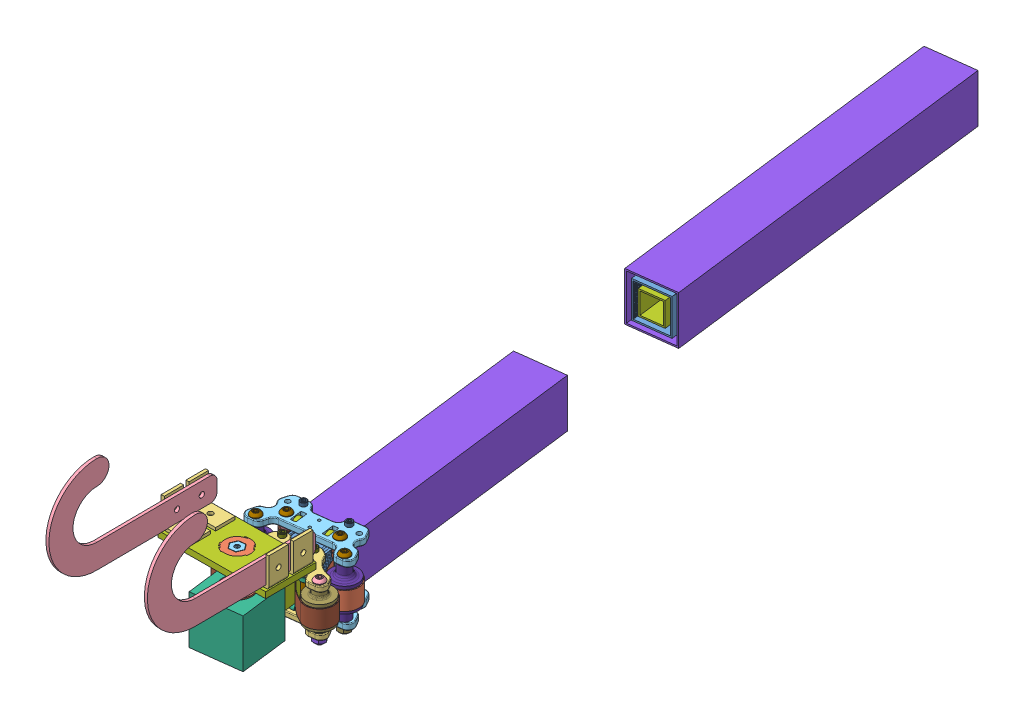
SolidWorks assembly climber prototype3, configuration Default. Lengths in mm.
Overall size (219.65 206.08 1008.89).
107 component instances, 43 part files, 29 mates.
Components (placement in the parent):
- ThriftyTelescopingTube(2)-1: ThriftyTelescopingTube(2) [Default] at origin size (219.65 74.15 857.68)
  - 2 x 2 Inch Stage-1: 2 x 2 Inch Stage [Default] at (1113.4745 353.0023 985.2524) size (183.93 74.15 806.3)
    - 1.5_inch_stage^2 x 2 Inch Stage-1: 1.5_inch_stage^2 x 2 Inch Stage [Default] at (-107.3783 0 -858.4701) size (133.34 47.37 731.79) (virtual)
      - 1.5x1.5 bar^1.5_inch_stage_2 x 2 Inch Stage-1: 1.5x1.5 bar^1.5_inch_stage_2 x 2 Inch Stage [Default] at (575.8182 404.7167 1377.5179) x (-0.992268 0 0.124114) z (-0.124114 0 -0.992268) size (38.1 38.1 711.2) (virtual)
      - 2x2StageInternalEndBlock^1.5_inch_stage_2 x 2 Inch Stage-1: 2x2StageInternalEndBlock^1.5_inch_stage_2 x 2 Inch Stage [Default] at (413.7616 573.8056 681.0462) x (-0.992268 0 0.124114) z (-0.124114 0 -0.992268) size (47.37 47.37 40.64) (virtual)
      - 94615A115_Brass Flanged Screw-to-Expand Inserts (1)^1.5_inch_stage_2 x 2 Inch Stage-1: 94615A115_Brass Flanged Screw-to-Expand Inserts (1)^1.5_inch_stage_2 x 2 Inch Stage [Default] at (431.7042 573.8056 688.4011) x (0.114575 0.384452 0.916007) z (-0.047716 0.923145 -0.381479) size (7.92 9.53 7.92) (virtual)
      - 97763A231_18-8 Stainless Steel Button Head Hex Drive Screws^1.5_inch_stage_2 x 2 Inch Stage-1: 97763A231_18-8 Stainless Steel Button Head Hex Drive Screws^1.5_inch_stage_2 x 2 Inch Stage [Default] at (398.9269 573.8691 692.501) x (0.124114 0.000773 0.992268) z (-0.992268 0 0.124114) size (9.17 9.17 12.09) (virtual)
    - 2x2ClimberPlateAssemblyNew^2 x 2 Inch Stage-1: 2x2ClimberPlateAssemblyNew^2 x 2 Inch Stage [Default] at (310.1471 56.4224 225.65) x (0.992268 0 -0.124114) z (0.124114 0 0.992268) size (102.18 13.04 44.45) (virtual)
      - 2x2NewClimberPlateConcept^2x2ClimberPlateAssemblyNew_2 x 2 Inch Stage-1: 2x2NewClimberPlateConcept^2x2ClimberPlateAssemblyNew_2 x 2 Inch Stage [Default] at (71.6924 542.7705 -285.0056) x (-1 0 0) z (0 1 0) size (102.18 44.45 8.76) (virtual)
      - 98381A545_ALLOY STEEL DOWEL PIN^2x2ClimberPlateAssemblyNew_2 x 2 Inch Stage-1: 98381A545_ALLOY STEEL DOWEL PIN^2x2ClimberPlateAssemblyNew_2 x 2 Inch Stage [Default] at (46.4194 542.6435 281.8589) x (-1 0 0) z (0 -0.467381 0.884056) size (34.92 6.35 6.35) (virtual)
      - TTB-0027_.50OD_.25ID_.188WD^2x2ClimberPlateAssemblyNew_2 x 2 Inch Stage-1: TTB-0027_.50OD_.25ID_.188WD^2x2ClimberPlateAssemblyNew_2 x 2 Inch Stage [Default] at (31.3382 542.6435 281.8589) x (0 0.013886 0.999904) z (-1 0 0) size (12.7 12.7 4.76) (virtual)
      - TTB-0027_.50OD_.25ID_.188WD^2x2ClimberPlateAssemblyNew_2 x 2 Inch Stage-2: TTB-0027_.50OD_.25ID_.188WD^2x2ClimberPlateAssemblyNew_2 x 2 Inch Stage [Default] at (61.5007 542.6435 281.8589) x (0 0.005291 0.999986) z (-1 0 0) size (12.7 12.7 4.76) (virtual)
    - 2x2ClimberPlateAssemblyNew^2 x 2 Inch Stage-2: 2x2ClimberPlateAssemblyNew^2 x 2 Inch Stage [Default] at (402.0161 1091.1635 214.1589) x (-0.992268 0 0.124114) z (0.124114 0 0.992268) size (102.18 13.04 44.45) (virtual)
      - 2x2NewClimberPlateConcept^2x2ClimberPlateAssemblyNew_2 x 2 Inch Stage-1: 2x2NewClimberPlateConcept^2x2ClimberPlateAssemblyNew_2 x 2 Inch Stage [Default] at (71.6924 542.7705 -285.0056) x (-1 0 0) z (0 1 0) size (102.18 44.45 8.76) (virtual)
      - 98381A545_ALLOY STEEL DOWEL PIN^2x2ClimberPlateAssemblyNew_2 x 2 Inch Stage-1: 98381A545_ALLOY STEEL DOWEL PIN^2x2ClimberPlateAssemblyNew_2 x 2 Inch Stage [Default] at (46.4194 542.6435 281.8589) x (-1 0 0) z (0 -0.467381 0.884056) size (34.92 6.35 6.35) (virtual)
      - TTB-0027_.50OD_.25ID_.188WD^2x2ClimberPlateAssemblyNew_2 x 2 Inch Stage-1: TTB-0027_.50OD_.25ID_.188WD^2x2ClimberPlateAssemblyNew_2 x 2 Inch Stage [Default] at (31.3382 542.6435 281.8589) x (0 0.013886 0.999904) z (-1 0 0) size (12.7 12.7 4.76) (virtual)
      - TTB-0027_.50OD_.25ID_.188WD^2x2ClimberPlateAssemblyNew_2 x 2 Inch Stage-2: TTB-0027_.50OD_.25ID_.188WD^2x2ClimberPlateAssemblyNew_2 x 2 Inch Stage [Default] at (61.5007 542.6435 281.8589) x (0 0.005291 0.999986) z (-1 0 0) size (12.7 12.7 4.76) (virtual)
    - 2x2 Box^2 x 2 Inch Stage-1: 2x2 Box^2 x 2 Inch Stage [Default] at (320.6921 548.3929 -267.6788) x (-0.992268 0 0.124114) z (0.124114 0 0.992268) size (50.8 50.8 762) (virtual)
    - 91255A529_NO THREADS_Button Head Hex Drive Screw (1)^2 x 2 Inch Stage-1: 91255A529_NO THREADS_Button Head Hex Drive Screw (1)^2 x 2 Inch Stage [Default] at (366.1553 609.0227 504.1716) x (0.396837 0 -0.917889) z (0 1 0) size (11.1 11.1 73.2) (virtual)
    - 90044A515_Black-Oxide Alloy Steel Socket Head Screw^2 x 2 Inch Stage-1: 90044A515_Black-Oxide Alloy Steel Socket Head Screw^2 x 2 Inch Stage [Default] at (410.673 605.6699 482.6046) x (0.993633 0 -0.112668) z (0 1 0) size (6.86 6.86 74.15) (virtual)
    - 90044A515_Black-Oxide Alloy Steel Socket Head Screw^2 x 2 Inch Stage-2: 90044A515_Black-Oxide Alloy Steel Socket Head Screw^2 x 2 Inch Stage [Default] at (367.8773 605.6699 487.9575) x (0.430705 0 0.902493) z (0 1 0) size (6.86 6.86 74.15) (virtual)
    - 91255A529_NO THREADS_Button Head Hex Drive Screw (1)^2 x 2 Inch Stage-2: 91255A529_NO THREADS_Button Head Hex Drive Screw (1)^2 x 2 Inch Stage [Default] at (351.7432 609.0227 521.973) x (-0.099638 0 0.995024) z (0 1 0) size (11.1 11.1 73.2) (virtual)
    - 91255A529_NO THREADS_Button Head Hex Drive Screw (1)^2 x 2 Inch Stage-3: 91255A529_NO THREADS_Button Head Hex Drive Screw (1)^2 x 2 Inch Stage [Default] at (434.6883 609.0227 511.5981) x (1 0 0) z (0 1 0) size (11.1 11.1 73.2) (virtual)
    - 91255A529_NO THREADS_Button Head Hex Drive Screw (1)^2 x 2 Inch Stage-4: 91255A529_NO THREADS_Button Head Hex Drive Screw (1)^2 x 2 Inch Stage [Default] at (416.3356 609.0227 497.895) x (0.998718 0 -0.050617) z (0 1 0) size (11.1 11.1 73.2) (virtual)
    - TTB-0027_.50OD_.25ID_.188WD^2 x 2 Inch Stage-1: TTB-0027_.50OD_.25ID_.188WD^2 x 2 Inch Stage [Default] at (416.3356 557.2004 497.895) x (-0.032207 0 0.999481) z (0 1 0) size (12.7 12.7 4.76) (virtual)
    - TTB-0027_.50OD_.25ID_.188WD^2 x 2 Inch Stage-2: TTB-0027_.50OD_.25ID_.188WD^2 x 2 Inch Stage [Default] at (416.3356 590.4617 497.895) x (-0.065423 0 0.997858) z (0 1 0) size (12.7 12.7 4.76) (virtual)
    - TTB-0027_.50OD_.25ID_.188WD^2 x 2 Inch Stage-3: TTB-0027_.50OD_.25ID_.188WD^2 x 2 Inch Stage [Default] at (366.1553 557.2004 504.1716) x (-0.065423 0 0.997858) z (0 1 0) size (12.7 12.7 4.76) (virtual)
    - TTB-0027_.50OD_.25ID_.188WD^2 x 2 Inch Stage-4: TTB-0027_.50OD_.25ID_.188WD^2 x 2 Inch Stage [Default] at (366.1553 590.4617 504.1716) x (-0.065423 0 0.997858) z (0 1 0) size (12.7 12.7 4.76) (virtual)
    - 90101A230_18-8 Stainless Steel Thin Nylon-Insert Locknut^2 x 2 Inch Stage-1: 90101A230_18-8 Stainless Steel Thin Nylon-Insert Locknut^2 x 2 Inch Stage [Default] at (434.6883 541.9159 511.5981) x (0.797272 0 -0.60362) z (-0.60362 0 -0.797272) size (11.11 5.2 12.83) (virtual)
    - 90101A230_18-8 Stainless Steel Thin Nylon-Insert Locknut^2 x 2 Inch Stage-2: 90101A230_18-8 Stainless Steel Thin Nylon-Insert Locknut^2 x 2 Inch Stage [Default] at (416.3356 541.9159 497.895) x (0.921386 0 0.388648) z (0.388648 0 -0.921386) size (11.11 5.2 12.83) (virtual)
    - 90101A230_18-8 Stainless Steel Thin Nylon-Insert Locknut^2 x 2 Inch Stage-3: 90101A230_18-8 Stainless Steel Thin Nylon-Insert Locknut^2 x 2 Inch Stage [Default] at (351.7432 541.9159 521.973) x (0.797272 0 -0.60362) z (-0.60362 0 -0.797272) size (11.11 5.2 12.83) (virtual)
    - 90101A230_18-8 Stainless Steel Thin Nylon-Insert Locknut^2 x 2 Inch Stage-4: 90101A230_18-8 Stainless Steel Thin Nylon-Insert Locknut^2 x 2 Inch Stage [Default] at (366.1553 541.9159 504.1716) x (0.797272 0 -0.60362) z (-0.60362 0 -0.797272) size (11.11 5.2 12.83) (virtual)
    - QuaterInchTelescopingSpacer^2 x 2 Inch Stage-1: QuaterInchTelescopingSpacer^2 x 2 Inch Stage [Default] at (391.2422 599.1929 504.1716) x (1 0 0) z (0 -1 0) size (9.27 9.27 6.35) (virtual)
    - QuaterInchTelescopingSpacer^2 x 2 Inch Stage-2: QuaterInchTelescopingSpacer^2 x 2 Inch Stage [Default] at (391.2422 554.8191 504.1844) x (1 0 0.000511) z (0 -1 0) size (9.27 9.27 6.35) (virtual)
    - 1.122InchTelescopingSpacer^2 x 2 Inch Stage-1: 1.122InchTelescopingSpacer^2 x 2 Inch Stage [Default] at (391.2422 588.0804 504.1716) x (1 0 0) z (0 -1 0) size (8.76 8.76 28.5) (virtual)
    - QuaterInchTelescopingSpacer^2 x 2 Inch Stage-3: QuaterInchTelescopingSpacer^2 x 2 Inch Stage [Default] at (440.4399 599.1929 504.8475) x (0.96083 0 0.277139) z (0 -1 0) size (9.27 9.27 6.35) (virtual)
    - QuaterInchTelescopingSpacer^2 x 2 Inch Stage-4: QuaterInchTelescopingSpacer^2 x 2 Inch Stage [Default] at (409.5553 554.8191 522.0482) x (-0.270275 0 0.962783) z (0 -1 0) size (9.27 9.27 6.35) (virtual)
    - 94615A115_Brass Flanged Screw-to-Expand Inserts (1)^2 x 2 Inch Stage-1: 94615A115_Brass Flanged Screw-to-Expand Inserts (1)^2 x 2 Inch Stage [Default] at (290.8052 573.8056 -165.8762) x (0.123955 0.050546 0.991) z (0.006274 -0.998722 0.050156) size (7.92 9.53 7.92) (virtual)
    - 97763A231_18-8 Stainless Steel Button Head Hex Drive Screws^2 x 2 Inch Stage-1: 97763A231_18-8 Stainless Steel Button Head Hex Drive Screws^2 x 2 Inch Stage [Default] at (323.7085 573.8691 -169.9917) x (-0.124114 0 -0.992268) z (0.992268 0 -0.124114) size (9.17 9.17 12.09) (virtual)
    - 1.122InchTelescopingSpacer^2 x 2 Inch Stage-2: 1.122InchTelescopingSpacer^2 x 2 Inch Stage [Default] at (441.4226 588.0804 497.895) x (1 0 0) z (0 -1 0) size (8.76 8.76 28.5) (virtual)
    - 1InchCFSpringRetentionSpacer_BaseStage^2 x 2 Inch Stage-1: 1InchCFSpringRetentionSpacer_BaseStage^2 x 2 Inch Stage [Default] at (351.7432 564.2679 521.973) x (1 0 0) z (0 -1 0) size (27.94 27.94 15.88) (virtual)
    - 1InchCFSpringRetentionSpacer_BaseStage^2 x 2 Inch Stage-2: 1InchCFSpringRetentionSpacer_BaseStage^2 x 2 Inch Stage [Default] at (434.6883 583.3179 511.5981) x (-0.043542 0 0.999052) z (0 1 0) size (27.94 27.94 15.88) (virtual)
    - 1InchCFSpringRetentionSpacer_BaseStage^2 x 2 Inch Stage-3: 1InchCFSpringRetentionSpacer_BaseStage^2 x 2 Inch Stage [Default] at (351.7432 583.3179 521.973) x (1 0 0) z (0 1 0) size (27.94 27.94 15.88) (virtual)
    - 1InchCFSpringRetentionSpacer_BaseStage^2 x 2 Inch Stage-4: 1InchCFSpringRetentionSpacer_BaseStage^2 x 2 Inch Stage [Default] at (434.6883 564.2679 511.5981) x (0.999991 0 -0.00417) z (0 -1 0) size (27.94 27.94 15.88) (virtual)
    - 90101A009_18-8 Stainless Steel Thin Nylon-Insert Locknut (1)^2 x 2 Inch Stage-1: 90101A009_18-8 Stainless Steel Thin Nylon-Insert Locknut (1)^2 x 2 Inch Stage [Default] at (368.252 541.9159 487.9106) x (0.797272 0 -0.60362) z (-0.60362 0 -0.797272) size (8.73 4.37 10.08) (virtual)
    - 9293K56_SpringRoller^2 x 2 Inch Stage-1: 9293K56_SpringRoller^2 x 2 Inch Stage [Default] at (351.7432 564.2679 521.973) x (0.41705 0 -0.908884) z (0 1 0) size (20.07 20.07 19.05) (virtual)
    - 9293K56_SpringRoller^2 x 2 Inch Stage-2: 9293K56_SpringRoller^2 x 2 Inch Stage [Default] at (434.6883 583.3179 511.5981) x (0.41705 0 0.908884) z (0 -1 0) size (20.07 20.07 19.05) (virtual)
    - 9293K56_Constant-Force Spring^2 x 2 Inch Stage-1: 9293K56_Constant-Force Spring^2 x 2 Inch Stage [Default] at (434.7326 573.7929 511.5599) x (0 -1 0) z (-0.934501 0 0.355959) size (19.06 41.04 33.21) (virtual)
    - 9293K56_Constant-Force Spring^2 x 2 Inch Stage-2: 9293K56_Constant-Force Spring^2 x 2 Inch Stage [Default] at (351.6902 573.7929 521.9484) x (0 1 0) z (0.996341 0 0.085466) size (19.06 41.04 33.21) (virtual)
    - 90101A009_18-8 Stainless Steel Thin Nylon-Insert Locknut (1)^2 x 2 Inch Stage-2: 90101A009_18-8 Stainless Steel Thin Nylon-Insert Locknut (1)^2 x 2 Inch Stage [Default] at (410.673 541.9159 482.6046) x (0.797272 0 -0.60362) z (-0.60362 0 -0.797272) size (8.73 4.37 10.08) (virtual)
  - Stage 2 BOM - 1.5 inch to 1 inch Kit^ThriftyTelescopingTube(2)-1: Stage 2 BOM - 1.5 inch to 1 inch Kit^ThriftyTelescopingTube(2) [Default] at (1071.3002 772.575 539.439) x (0.992268 0 -0.124114) z (0.124114 0 0.992268) size (125.22 66.32 768.66) (virtual)
    - 1.5ClimberPlateNewDesign^Stage 2 BOM - 1.5 inch to 1 inch Kit_ThriftyTelescopingTube(2)-1: 1.5ClimberPlateNewDesign^Stage 2 BOM - 1.5 inch to 1 inch Kit_ThriftyTelescopingTube(2) [Default] at (293.5653 129.5314 1017.7273) x (1 0 0) z (0 1 0) size (98.65 41.27 8) (virtual)
    - 1.5ClimberPlateNewDesign^Stage 2 BOM - 1.5 inch to 1 inch Kit_ThriftyTelescopingTube(2)-2: 1.5ClimberPlateNewDesign^Stage 2 BOM - 1.5 inch to 1 inch Kit_ThriftyTelescopingTube(2) [Default] at (331.6653 179.0614 1017.7273) x (-1 0 0) z (0 -1 0) size (98.65 41.27 8) (virtual)
    - 91255A528_NO THREADS_Button Head Hex Drive Screw^Stage 2 BOM - 1.5 inch to 1 inch Kit_ThriftyTelescopingTube(2)-1: 91255A528_NO THREADS_Button Head Hex Drive Screw^Stage 2 BOM - 1.5 inch to 1 inch Kit_ThriftyTelescopingTube(2) [Default] at (354.2078 182.4142 1039.3173) x (0.997583 0 0.069478) z (0 1 0) size (11.1 11.1 60.5) (virtual)
    - 91255A528_NO THREADS_Button Head Hex Drive Screw^Stage 2 BOM - 1.5 inch to 1 inch Kit_ThriftyTelescopingTube(2)-2: 91255A528_NO THREADS_Button Head Hex Drive Screw^Stage 2 BOM - 1.5 inch to 1 inch Kit_ThriftyTelescopingTube(2) [Default] at (331.551 182.4142 1025.9823) x (1 0 0.000115) z (0 1 0) size (11.1 11.1 60.5) (virtual)
    - 91255A528_NO THREADS_Button Head Hex Drive Screw^Stage 2 BOM - 1.5 inch to 1 inch Kit_ThriftyTelescopingTube(2)-3: 91255A528_NO THREADS_Button Head Hex Drive Screw^Stage 2 BOM - 1.5 inch to 1 inch Kit_ThriftyTelescopingTube(2) [Default] at (293.6796 182.4142 1025.9823) x (0.942114 0 0.335293) z (0 1 0) size (11.1 11.1 60.5) (virtual)
    - 91255A528_NO THREADS_Button Head Hex Drive Screw^Stage 2 BOM - 1.5 inch to 1 inch Kit_ThriftyTelescopingTube(2)-4: 91255A528_NO THREADS_Button Head Hex Drive Screw^Stage 2 BOM - 1.5 inch to 1 inch Kit_ThriftyTelescopingTube(2) [Default] at (271.0228 182.4142 1039.3173) x (1 0 0) z (0 1 0) size (11.1 11.1 60.5) (virtual)
    - 98381A542_ALLOY STEEL DOWEL PIN^Stage 2 BOM - 1.5 inch to 1 inch Kit_ThriftyTelescopingTube(2)-1: 98381A542_ALLOY STEEL DOWEL PIN^Stage 2 BOM - 1.5 inch to 1 inch Kit_ThriftyTelescopingTube(2) [Default] at (312.5899 173.2194 1025.9545) x (1 0 0) z (0 -0.047568 0.998868) size (25.4 6.35 6.35) (virtual)
    - 98381A542_ALLOY STEEL DOWEL PIN^Stage 2 BOM - 1.5 inch to 1 inch Kit_ThriftyTelescopingTube(2)-2: 98381A542_ALLOY STEEL DOWEL PIN^Stage 2 BOM - 1.5 inch to 1 inch Kit_ThriftyTelescopingTube(2) [Default] at (312.5899 135.3734 1025.9545) x (1 0 0) z (0 -0.129807 0.991539) size (25.4 6.35 6.35) (virtual)
    - TTB-0027_.50OD_.25ID_.188WD^Stage 2 BOM - 1.5 inch to 1 inch Kit_ThriftyTelescopingTube(2)-1: TTB-0027_.50OD_.25ID_.188WD^Stage 2 BOM - 1.5 inch to 1 inch Kit_ThriftyTelescopingTube(2) [Default] at (322.7054 135.3734 1025.9545) x (0 -0.059569 0.998224) z (-1 0 0) size (12.7 12.7 4.76) (virtual)
    - TTB-0027_.50OD_.25ID_.188WD^Stage 2 BOM - 1.5 inch to 1 inch Kit_ThriftyTelescopingTube(2)-2: TTB-0027_.50OD_.25ID_.188WD^Stage 2 BOM - 1.5 inch to 1 inch Kit_ThriftyTelescopingTube(2) [Default] at (302.4743 135.3734 1025.9545) x (0 0.249065 0.968487) z (-1 0 0) size (12.7 12.7 4.76) (virtual)
    - TTB-0027_.50OD_.25ID_.188WD^Stage 2 BOM - 1.5 inch to 1 inch Kit_ThriftyTelescopingTube(2)-3: TTB-0027_.50OD_.25ID_.188WD^Stage 2 BOM - 1.5 inch to 1 inch Kit_ThriftyTelescopingTube(2) [Default] at (293.6796 166.19 1025.9823) x (-0.99026 0 0.139228) z (0 1 0) size (12.7 12.7 4.76) (virtual)
    - TTB-0027_.50OD_.25ID_.188WD^Stage 2 BOM - 1.5 inch to 1 inch Kit_ThriftyTelescopingTube(2)-4: TTB-0027_.50OD_.25ID_.188WD^Stage 2 BOM - 1.5 inch to 1 inch Kit_ThriftyTelescopingTube(2) [Default] at (293.6796 142.2505 1025.9823) x (1 0 0) z (0 1 0) size (12.7 12.7 4.76) (virtual)
    - TTB-0027_.50OD_.25ID_.188WD^Stage 2 BOM - 1.5 inch to 1 inch Kit_ThriftyTelescopingTube(2)-5: TTB-0027_.50OD_.25ID_.188WD^Stage 2 BOM - 1.5 inch to 1 inch Kit_ThriftyTelescopingTube(2) [Default] at (331.551 166.19 1025.9823) x (-0.070413 0 0.997518) z (0 1 0) size (12.7 12.7 4.76) (virtual)
    - TTB-0027_.50OD_.25ID_.188WD^Stage 2 BOM - 1.5 inch to 1 inch Kit_ThriftyTelescopingTube(2)-6: TTB-0027_.50OD_.25ID_.188WD^Stage 2 BOM - 1.5 inch to 1 inch Kit_ThriftyTelescopingTube(2) [Default] at (302.4743 173.2194 1025.9545) x (0 -0.065423 0.997858) z (-1 0 0) size (12.7 12.7 4.76) (virtual)
    - TTB-0027_.50OD_.25ID_.188WD^Stage 2 BOM - 1.5 inch to 1 inch Kit_ThriftyTelescopingTube(2)-7: TTB-0027_.50OD_.25ID_.188WD^Stage 2 BOM - 1.5 inch to 1 inch Kit_ThriftyTelescopingTube(2) [Default] at (322.7054 173.2194 1025.9545) x (0 0.136778 0.990602) z (-1 0 0) size (12.7 12.7 4.76) (virtual)
    - TTB-0027_.50OD_.25ID_.188WD^Stage 2 BOM - 1.5 inch to 1 inch Kit_ThriftyTelescopingTube(2)-8: TTB-0027_.50OD_.25ID_.188WD^Stage 2 BOM - 1.5 inch to 1 inch Kit_ThriftyTelescopingTube(2) [Default] at (331.551 142.2505 1025.9823) x (1 0 0) z (0 1 0) size (12.7 12.7 4.76) (virtual)
    - 1x1^Stage 2 BOM - 1.5 inch to 1 inch Kit_ThriftyTelescopingTube(2)-1: 1x1^Stage 2 BOM - 1.5 inch to 1 inch Kit_ThriftyTelescopingTube(2) [Default] at (299.8518 166.9329 770.3868) x (0 -1 0) z (-1 0 0) size (25.4 711.2 25.4) (virtual)
    - 90101A230_18-8 Stainless Steel Thin Nylon-Insert Locknut^Stage 2 BOM - 1.5 inch to 1 inch Kit_ThriftyTelescopingTube(2)-1: 90101A230_18-8 Stainless Steel Thin Nylon-Insert Locknut^Stage 2 BOM - 1.5 inch to 1 inch Kit_ThriftyTelescopingTube(2) [Default] at (293.6796 129.5314 1025.9823) x (0.866025 0 -0.5) z (-0.5 0 -0.866025) size (11.11 5.2 12.83) (virtual)
    - 90101A230_18-8 Stainless Steel Thin Nylon-Insert Locknut^Stage 2 BOM - 1.5 inch to 1 inch Kit_ThriftyTelescopingTube(2)-2: 90101A230_18-8 Stainless Steel Thin Nylon-Insert Locknut^Stage 2 BOM - 1.5 inch to 1 inch Kit_ThriftyTelescopingTube(2) [Default] at (354.2078 129.5314 1039.3173) x (-0.866025 0 -0.5) z (-0.5 0 0.866025) size (11.11 5.2 12.83) (virtual)
    - 90101A230_18-8 Stainless Steel Thin Nylon-Insert Locknut^Stage 2 BOM - 1.5 inch to 1 inch Kit_ThriftyTelescopingTube(2)-3: 90101A230_18-8 Stainless Steel Thin Nylon-Insert Locknut^Stage 2 BOM - 1.5 inch to 1 inch Kit_ThriftyTelescopingTube(2) [Default] at (331.551 129.5314 1025.9823) x (0.866025 0 0.5) z (0.5 0 -0.866025) size (11.11 5.2 12.83) (virtual)
    - 90101A230_18-8 Stainless Steel Thin Nylon-Insert Locknut^Stage 2 BOM - 1.5 inch to 1 inch Kit_ThriftyTelescopingTube(2)-4: 90101A230_18-8 Stainless Steel Thin Nylon-Insert Locknut^Stage 2 BOM - 1.5 inch to 1 inch Kit_ThriftyTelescopingTube(2) [Default] at (271.0228 129.5314 1039.3173) x (0.866025 0 0.5) z (0.5 0 -0.866025) size (11.11 5.2 12.83) (virtual)
    - .607TelescopingSpacer^Stage 2 BOM - 1.5 inch to 1 inch Kit_ThriftyTelescopingTube(2)-1: .607TelescopingSpacer^Stage 2 BOM - 1.5 inch to 1 inch Kit_ThriftyTelescopingTube(2) [Default] at (354.9872 144.6317 1017.0327) x (0.934202 0 -0.356745) z (0 1 0) size (9.02 9.02 19.18) (virtual)
    - .607TelescopingSpacer^Stage 2 BOM - 1.5 inch to 1 inch Kit_ThriftyTelescopingTube(2)-2: .607TelescopingSpacer^Stage 2 BOM - 1.5 inch to 1 inch Kit_ThriftyTelescopingTube(2) [Default] at (318.7665 144.6317 1026.006) x (1 0 0.000943) z (0 1 0) size (9.02 9.02 19.18) (virtual)
    - .188TelescopingSpacer^Stage 2 BOM - 1.5 inch to 1 inch Kit_ThriftyTelescopingTube(2)-1: .188TelescopingSpacer^Stage 2 BOM - 1.5 inch to 1 inch Kit_ThriftyTelescopingTube(2) [Default] at (356.6379 173.3464 1025.9823) x (1 0 0) z (0 -1 0) size (8.81 8.81 4.78) (virtual)
    - .188TelescopingSpacer^Stage 2 BOM - 1.5 inch to 1 inch Kit_ThriftyTelescopingTube(2)-2: .188TelescopingSpacer^Stage 2 BOM - 1.5 inch to 1 inch Kit_ThriftyTelescopingTube(2) [Default] at (318.7665 173.3464 1025.9823) x (1 0 0) z (0 -1 0) size (8.81 8.81 4.78) (virtual)
    - .188TelescopingSpacer^Stage 2 BOM - 1.5 inch to 1 inch Kit_ThriftyTelescopingTube(2)-3: .188TelescopingSpacer^Stage 2 BOM - 1.5 inch to 1 inch Kit_ThriftyTelescopingTube(2) [Default] at (282.8338 139.8692 1048.6036) x (-0.432328 0 0.901716) z (0 -1 0) size (8.81 8.81 4.78) (virtual)
    - .188TelescopingSpacer^Stage 2 BOM - 1.5 inch to 1 inch Kit_ThriftyTelescopingTube(2)-4: .188TelescopingSpacer^Stage 2 BOM - 1.5 inch to 1 inch Kit_ThriftyTelescopingTube(2) [Default] at (326.9008 139.8692 1001.3302) x (-0.18536 0 -0.982671) z (0 -1 0) size (8.81 8.81 4.78) (virtual)
    - 9293K56_Constant-Force Spring^Stage 2 BOM - 1.5 inch to 1 inch Kit_ThriftyTelescopingTube(2)-1: 9293K56_Constant-Force Spring^Stage 2 BOM - 1.5 inch to 1 inch Kit_ThriftyTelescopingTube(2) [Default] at (354.2389 154.2964 1039.2678) x (0 -1 0) z (-0.788944 0 0.614465) size (19.06 41.04 33.21) (virtual)
    - 1InchCFSpringRetentionSpacer^Stage 2 BOM - 1.5 inch to 1 inch Kit_ThriftyTelescopingTube(2)-1: 1InchCFSpringRetentionSpacer^Stage 2 BOM - 1.5 inch to 1 inch Kit_ThriftyTelescopingTube(2) [Default] at (271.0228 144.7714 1039.3173) x (0.41705 0 0.908884) z (0 -1 0) size (27.94 27.94 9.53) (virtual)
    - 1InchCFSpringRetentionSpacer^Stage 2 BOM - 1.5 inch to 1 inch Kit_ThriftyTelescopingTube(2)-2: 1InchCFSpringRetentionSpacer^Stage 2 BOM - 1.5 inch to 1 inch Kit_ThriftyTelescopingTube(2) [Default] at (354.2078 144.7714 1039.3173) x (0.383782 0 0.923424) z (0 -1 0) size (27.94 27.94 9.53) (virtual)
    - 1InchCFSpringRetentionSpacer^Stage 2 BOM - 1.5 inch to 1 inch Kit_ThriftyTelescopingTube(2)-3: 1InchCFSpringRetentionSpacer^Stage 2 BOM - 1.5 inch to 1 inch Kit_ThriftyTelescopingTube(2) [Default] at (354.2078 163.8214 1039.3173) x (0.830028 0 -0.557722) z (0 1 0) size (27.94 27.94 9.53) (virtual)
    - 1InchCFSpringRetentionSpacer^Stage 2 BOM - 1.5 inch to 1 inch Kit_ThriftyTelescopingTube(2)-4: 1InchCFSpringRetentionSpacer^Stage 2 BOM - 1.5 inch to 1 inch Kit_ThriftyTelescopingTube(2) [Default] at (271.0228 163.8214 1039.3173) x (0.383782 0 -0.923424) z (0 1 0) size (27.94 27.94 9.53) (virtual)
    - 9293K56_Constant-Force Spring^Stage 2 BOM - 1.5 inch to 1 inch Kit_ThriftyTelescopingTube(2)-2: 9293K56_Constant-Force Spring^Stage 2 BOM - 1.5 inch to 1 inch Kit_ThriftyTelescopingTube(2) [Default] at (270.9861 154.2964 1039.2718) x (0 1 0) z (0.855643 0 0.517566) size (19.06 41.04 33.21) (virtual)
    - 9293K56_SpringRoller^Stage 2 BOM - 1.5 inch to 1 inch Kit_ThriftyTelescopingTube(2)-1: 9293K56_SpringRoller^Stage 2 BOM - 1.5 inch to 1 inch Kit_ThriftyTelescopingTube(2) [Default] at (271.0228 163.8214 1039.3173) x (0.416799 0 0.908999) z (0 -1 0) size (20.07 20.07 19.05) (virtual)
    - 1x1StageInternalEndBlock^Stage 2 BOM - 1.5 inch to 1 inch Kit_ThriftyTelescopingTube(2)-1: 1x1StageInternalEndBlock^Stage 2 BOM - 1.5 inch to 1 inch Kit_ThriftyTelescopingTube(2) [Default] at (312.6153 154.2964 363.9868) x (-1 0 0) z (0 0 -1) size (34.67 34.67 40) (virtual)
    - 90101A009_18-8 Stainless Steel Thin Nylon-Insert Locknut (1)^Stage 2 BOM - 1.5 inch to 1 inch Kit_ThriftyTelescopingTube(2)-1: 90101A009_18-8 Stainless Steel Thin Nylon-Insert Locknut (1)^Stage 2 BOM - 1.5 inch to 1 inch Kit_ThriftyTelescopingTube(2) [Default] at (327.8299 129.5314 1011.3773) x (0.866025 0 0.5) z (0.5 0 -0.866025) size (8.73 4.37 10.08) (virtual)
    - 90101A009_18-8 Stainless Steel Thin Nylon-Insert Locknut (1)^Stage 2 BOM - 1.5 inch to 1 inch Kit_ThriftyTelescopingTube(2)-2: 90101A009_18-8 Stainless Steel Thin Nylon-Insert Locknut (1)^Stage 2 BOM - 1.5 inch to 1 inch Kit_ThriftyTelescopingTube(2) [Default] at (297.4007 129.5314 1011.3773) x (-0.866025 0 -0.5) z (-0.5 0 0.866025) size (8.73 4.37 10.08) (virtual)
    - 90044A513_Black-Oxide Alloy Steel Socket Head Screw^Stage 2 BOM - 1.5 inch to 1 inch Kit_ThriftyTelescopingTube(2)-1: 90044A513_Black-Oxide Alloy Steel Socket Head Screw^Stage 2 BOM - 1.5 inch to 1 inch Kit_ThriftyTelescopingTube(2) [Default] at (297.4007 179.0614 1011.3773) x (0.353324 0 0.935501) z (0 1 0) size (10.11 10 66.32) (virtual)
    - 90044A513_Black-Oxide Alloy Steel Socket Head Screw^Stage 2 BOM - 1.5 inch to 1 inch Kit_ThriftyTelescopingTube(2)-2: 90044A513_Black-Oxide Alloy Steel Socket Head Screw^Stage 2 BOM - 1.5 inch to 1 inch Kit_ThriftyTelescopingTube(2) [Default] at (327.8299 179.0614 1011.3773) x (1 0 0) z (0 1 0) size (10.11 10 66.32) (virtual)
    - 94615A212_Brass Flanged Screw-to-Expand Inserts (1)^Stage 2 BOM - 1.5 inch to 1 inch Kit_ThriftyTelescopingTube(2)-1: 94615A212_Brass Flanged Screw-to-Expand Inserts (1)^Stage 2 BOM - 1.5 inch to 1 inch Kit_ThriftyTelescopingTube(2) [Default] at (301.9473 154.2964 373.5118) x (0 -0.59679 -0.802398) z (0 0.802398 -0.59679) size (7.14 7.14 7.14) (virtual)
    - 94615A212_Brass Flanged Screw-to-Expand Inserts (1)^Stage 2 BOM - 1.5 inch to 1 inch Kit_ThriftyTelescopingTube(2)-2: 94615A212_Brass Flanged Screw-to-Expand Inserts (1)^Stage 2 BOM - 1.5 inch to 1 inch Kit_ThriftyTelescopingTube(2) [Default] at (323.2833 154.2964 373.5118) x (0 0.670342 -0.742052) z (0 -0.742052 -0.670342) size (7.14 7.14 7.14) (virtual)
    - 97763A504_18-8 Stainless Steel Button Head Hex Drive Screws^Stage 2 BOM - 1.5 inch to 1 inch Kit_ThriftyTelescopingTube(2)-1: 97763A504_18-8 Stainless Steel Button Head Hex Drive Screws^Stage 2 BOM - 1.5 inch to 1 inch Kit_ThriftyTelescopingTube(2) [Default] at (302.0806 154.2964 373.5118) x (0 0 1) z (-1 0 0) size (7.92 7.92 10.15) (virtual)
    - 97763A504_18-8 Stainless Steel Button Head Hex Drive Screws^Stage 2 BOM - 1.5 inch to 1 inch Kit_ThriftyTelescopingTube(2)-2: 97763A504_18-8 Stainless Steel Button Head Hex Drive Screws^Stage 2 BOM - 1.5 inch to 1 inch Kit_ThriftyTelescopingTube(2) [Default] at (323.0229 154.2964 373.5118) x (0 0 -1) z (1 0 0) size (7.92 7.92 10.15) (virtual)
    - 1.5x1.5 bar^Stage 2 BOM - 1.5 inch to 1 inch Kit_ThriftyTelescopingTube(2)-1: 1.5x1.5 bar^Stage 2 BOM - 1.5 inch to 1 inch Kit_ThriftyTelescopingTube(2) [Default] at (386.9135 -14.856 1017.7273) x (-1 0 0) z (0 0 -1) size (38.1 38.1 711.2) (virtual)
    - 9293K56_SpringRoller^Stage 2 BOM - 1.5 inch to 1 inch Kit_ThriftyTelescopingTube(2)-2: 9293K56_SpringRoller^Stage 2 BOM - 1.5 inch to 1 inch Kit_ThriftyTelescopingTube(2) [Default] at (354.2078 163.8214 1039.3173) x (0.416799 0 0.908999) z (0 -1 0) size (20.07 20.07 19.05) (virtual)
- half in hex bearing for clibmer-1: half in hex bearing for clibmer [Default] at (1516.0789 990.308 1577.6097) x (0.992268 0 -0.124114) z (0 -1 0) size (31.12 31.12 7.93)
- Bracket for climber prototype-3: Bracket for climber prototype [Default] at (1475.5943 991.8955 1601.2458) x (-0.999978 0 0.006611) z (-0.006611 0 -0.999978) size (30.99 30.99 20.57)
- Bracket for climber prototype-4: Bracket for climber prototype [Default] at (1556.5635 991.8955 1553.9736) x (0.999978 0 -0.006611) z (0.006611 0 0.999978) size (30.99 30.99 20.57)
- Bracket for climber prototype-5: Bracket for climber prototype [Default] at (1475.4213 991.8955 1575.0844) x (-0.999978 0 0.006611) z (-0.006611 0 -0.999978) size (30.99 30.99 20.57)
- Bracket for climber prototype-6: Bracket for climber prototype [Default] at (1556.7365 991.8955 1580.135) x (0.999978 0 -0.006611) z (0.006611 0 0.999978) size (30.99 30.99 20.57)
- Candy cane claw-1: Candy cane claw [Default] at (1466.1023 1010.6048 1548.6432) x (0 -1 0) z (-0.999978 0 0.006611) size (101.6 177.8 3.17)
- Candy cane claw-2: Candy cane claw [Default] at (1568.8431 1010.6048 1547.964) x (0 -1 0) z (-0.999978 0 0.006611) size (101.6 177.8 3.17)
- Hex shaft for climber-1: Hex shaft for climber [Default] at (1516.0789 914.108 1577.6097) x (0 1 0) z (0.992268 0 -0.124114) size (89.82 12 13.86)
- block for climber seprate-1: block for climber seprate [Default] at (1512.9264 926.808 1552.4061) x (0 1 0) z (0.992268 0 -0.124114) size (50.8 50.8 50.8)
- half in hex bearing for clibmer-2: half in hex bearing for clibmer [Default] at (1516.0789 945.858 1577.6097) x (-0.166109 0 -0.986107) z (0 1 0) size (31.12 31.12 7.93)
- wood piece for pivot in climber-1: wood piece for pivot in climber [Default] at (1516.0789 983.958 1577.6097) x (0 1 0) z (-0.999978 0 0.006611) size (6.35 53.34 112.27)
Mates (geometry in assembly coordinates):
- Concentric12: concentric anti-aligned: cylinder of Bracket for climber prototype-5 through (1490.847 1005.802 1564.6952) axis (-0.999978 0 0.006611) radius 2.667; cylinder of Candy cane claw-1 through (1463.0346 1005.802 1564.8791) axis (0.999978 0 -0.006611) radius 2.794
- Parallel10: parallel anti-aligned: cylinder of Bracket for climber prototype-3 through (1491.0199 1005.802 1590.8566) axis (-0.999978 0 0.006611) radius 2.667; cylinder of Candy cane claw-1 through (1463.2075 1005.802 1591.0405) axis (0.999978 0 -0.006611) radius 2.794
- Coincident15: coincident anti-aligned: plane of Bracket for climber prototype-3 through (1463.1395 993.483 1580.7537) normal (0.999978 0 -0.006611); plane of Candy cane claw-1 through (1463.7669 1043.9604 1675.6614) normal (-0.999978 0 0.006611)
- Concentric14: concentric anti-aligned: cylinder of Bracket for climber prototype-3 through (1491.0199 1005.802 1590.8566) axis (-0.999978 0 0.006611) radius 2.667; cylinder of Candy cane claw-1 through (1463.2075 1005.802 1591.0405) axis (0.999978 0 -0.006611) radius 2.794
- Concentric15: concentric aligned: cylinder of Bracket for climber prototype-6 through (1541.3108 1005.802 1590.5242) axis (0.999978 0 -0.006611) radius 2.667; cylinder of Candy cane claw-2 through (1565.9483 1005.802 1590.3613) axis (0.999978 0 -0.006611) radius 2.794
- Concentric16: concentric aligned: cylinder of Bracket for climber prototype-4 through (1541.1379 1005.802 1564.3628) axis (0.999978 0 -0.006611) radius 2.667; cylinder of Candy cane claw-2 through (1565.7753 1005.802 1564.1999) axis (0.999978 0 -0.006611) radius 2.794
- Coincident16: coincident anti-aligned: plane of Bracket for climber prototype-6 through (1569.1912 993.483 1600.6271) normal (-0.999978 0 0.006611); plane of Candy cane claw-2 through (1569.6826 1043.9604 1674.9612) normal (0.999978 0 -0.006611)
- Coincident17: coincident aligned: plane of Hex shaft for climber-1 through (1516.0789 901.408 1577.6097) normal (0 -1 0); plane of block for climber seprate-1 through (1544.435 901.408 1599.6608) normal (0 -1 0)
- Coincident18: coincident anti-aligned: plane of Hex shaft for climber-1 through (1520.2609 901.408 1583.1334) normal (0.921386 0 0.388648); plane of block for climber seprate-1 through (1520.2609 901.408 1583.1334) normal (-0.921386 0 -0.388648)
- Coincident19: coincident anti-aligned: plane of Hex shaft for climber-1 through (1513.3863 901.408 1583.9933) normal (0.124114 0 0.992268); plane of block for climber seprate-1 through (1513.3863 901.408 1583.9933) normal (-0.124114 0 -0.992268)
- Coincident20: coincident anti-aligned: plane of block for climber seprate-1 through (1516.0789 945.858 1577.6097) normal (0 1 0); plane of half in hex bearing for clibmer-2 through (1516.0789 945.858 1577.6097) normal (0 -1 0)
- Concentric17: concentric anti-aligned: circle of block for climber seprate-1; cylinder of half in hex bearing for clibmer-2 through (1516.0789 953.7853 1577.6097) axis (0 -1 0) radius 14.2875
- Concentric18: concentric aligned: circle of Hex shaft for climber-1; circle of wood piece for pivot in climber-1
- Coincident23: coincident aligned: plane of Hex shaft for climber-1 through (1516.0789 990.308 1577.6097) normal (0 1 0); plane of wood piece for pivot in climber-1 through (1516.0789 990.308 1577.6097) normal (0 1 0)
- Concentric21: concentric aligned: circle of half in hex bearing for clibmer-1; circle of Hex shaft for climber-1
- Coincident32: coincident aligned: plane of half in hex bearing for clibmer-1 through (1516.0789 990.308 1577.6097) normal (0 1 0); plane of wood piece for pivot in climber-1 through (1516.0789 990.308 1577.6097) normal (0 1 0)
- Parallel15: parallel anti-aligned: line of Bracket for climber prototype-3 through (1490.9519 990.308 1580.5699) axis (-0.999978 0 0.006611); line of Bracket for climber prototype-6 through (1541.2428 990.308 1580.2374) axis (0.999978 0 -0.006611)
- Parallel16: parallel anti-aligned: line of Bracket for climber prototype-4 through (1541.2059 990.308 1574.6495) axis (0.999978 0 -0.006611); line of Bracket for climber prototype-5 through (1490.915 990.308 1574.982) axis (-0.999978 0 0.006611)
- Coincident35: coincident anti-aligned: plane of ThriftyTelescopingTube(2)-1/Stage 2 BOM - 1.5 inch to 1 inch Kit^ThriftyTelescopingTube(2)-1/1x1^Stage 2 BOM - 1.5 inch to 1 inch Kit_ThriftyTelescopingTube(2)-1 through (1502.2791 939.508 1569.0966) normal (0.124114 0 0.992268); plane of block for climber seprate-1 through (1514.8179 926.808 1567.5283) normal (-0.124114 0 -0.992268)
- Coincident36: coincident anti-aligned: plane of ThriftyTelescopingTube(2)-1/Stage 2 BOM - 1.5 inch to 1 inch Kit^ThriftyTelescopingTube(2)-1/1x1^Stage 2 BOM - 1.5 inch to 1 inch Kit_ThriftyTelescopingTube(2)-1 through (1502.2791 939.508 1569.0966) normal (0 1 0); plane of block for climber seprate-1 through (1527.4197 939.508 1565.952) normal (0 -1 0)
- Coincident37: coincident anti-aligned: plane of ThriftyTelescopingTube(2)-1/Stage 2 BOM - 1.5 inch to 1 inch Kit^ThriftyTelescopingTube(2)-1/1x1^Stage 2 BOM - 1.5 inch to 1 inch Kit_ThriftyTelescopingTube(2)-1 through (1525.9075 937.9205 1566.1412) normal (-0.992268 0 0.124114); plane of block for climber seprate-1 through (1525.9075 915.632 1566.1412) normal (0.992268 0 -0.124114)
- Coincident38: coincident anti-aligned: plane of Bracket for climber prototype-5 through (1462.9666 993.483 1554.5923) normal (0.999978 0 -0.006611); plane of Candy cane claw-1 through (1463.7669 1043.9604 1675.6614) normal (-0.999978 0 0.006611)
- Concentric23: concentric aligned: cylinder of Bracket for climber prototype-3 through (1475.5262 1021.296 1590.9591) axis (0 -1 0) radius 2.794; cylinder of wood piece for pivot in climber-1 through (1475.5262 990.308 1590.9591) axis (0 -1 0) radius 3.175
- Concentric24: concentric aligned: cylinder of Bracket for climber prototype-5 through (1475.3533 1021.296 1564.7976) axis (0 -1 0) radius 2.794; cylinder of wood piece for pivot in climber-1 through (1475.3533 990.308 1564.7976) axis (0 -1 0) radius 3.175
- Concentric25: concentric aligned: cylinder of Bracket for climber prototype-6 through (1556.8045 1021.296 1590.4218) axis (0 -1 0) radius 2.794; cylinder of wood piece for pivot in climber-1 through (1556.8045 990.308 1590.4218) axis (0 -1 0) radius 3.175
- Concentric26: concentric aligned: cylinder of Bracket for climber prototype-4 through (1556.6315 1021.296 1564.2603) axis (0 -1 0) radius 2.794; cylinder of wood piece for pivot in climber-1 through (1556.6315 990.308 1564.2603) axis (0 -1 0) radius 3.175
- Coincident40: coincident anti-aligned: plane of Bracket for climber prototype-6 through (1572.3661 990.308 1600.6061) normal (0 -1 0); plane of wood piece for pivot in climber-1 through (1516.0789 990.308 1577.6097) normal (0 1 0)
- Coincident41: coincident anti-aligned: plane of Bracket for climber prototype-3 through (1459.9646 990.308 1580.7747) normal (0 -1 0); plane of wood piece for pivot in climber-1 through (1516.0789 990.308 1577.6097) normal (0 1 0)
- Parallel18: parallel anti-aligned: plane of half in hex bearing for clibmer-1 through (1508.8032 982.3806 1578.5197) normal (0.797272 0 -0.60362); plane of Hex shaft for climber-1 through (1509.2043 901.408 1578.4696) normal (-0.797272 0 0.60362)
